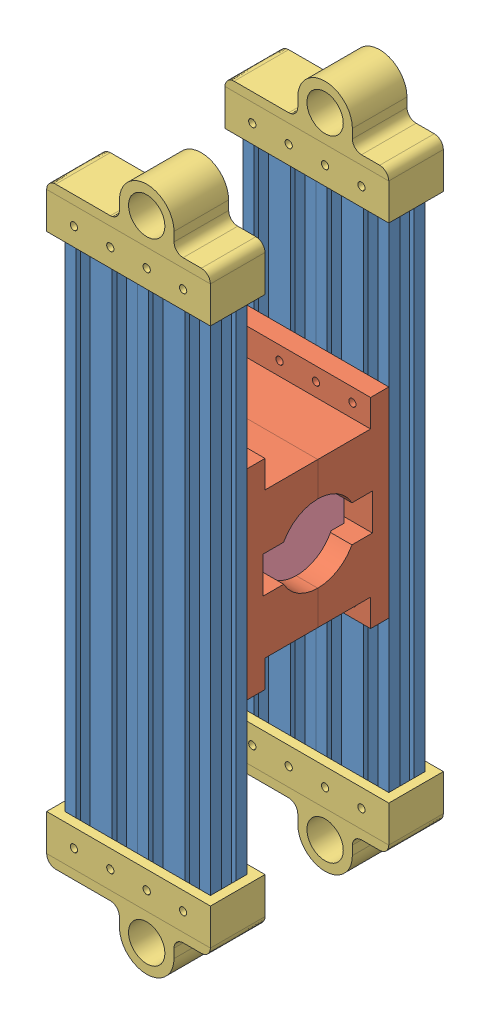
SolidWorks assembly Suspension complète v1.0, configuration Défaut. Lengths in mm.
Overall size (108 375.2 128).
13 component instances, 4 part files, 8 mates.
Components (placement in the parent):
- suspension1.0-1: suspension1.0 [Défaut] at (22.9768 47.3226 -340) size (90 375.2 64)
  - profilé 370-40-1: profilé 370-40 [Défaut] at (-82.9768 -150.3226 340) size (40 316 20)
  - profilé 370-40-2: profilé 370-40 [Défaut] at (-42.9768 -150.3226 340) size (40 316 20)
  - support moteur-2: support moteur [Défaut] at (-47.9768 7.6774 359.5) x (0 -1 0) z (-1 0 0) size (110 39 80)
  - fin profilé-1: fin profilé [Défaut] at (-62.9768 165.6774 330) x (-1 0 0) z (0 -1 0) size (90 30 49.6)
  - fin profilé-2: fin profilé [Défaut] at (-62.9768 -150.3226 330) x (-1 0 0) z (0 1 0) size (90 30 49.6)
- suspension1.0-2: suspension1.0 [Défaut] at (22.9768 62.6774 418) x (1 0 0) z (0 0 -1) size (90 375.2 64)
  - profilé 370-40-1: profilé 370-40 [Défaut] at (-82.9768 -150.3226 340) size (40 316 20)
  - profilé 370-40-2: profilé 370-40 [Défaut] at (-42.9768 -150.3226 340) size (40 316 20)
  - support moteur-2: support moteur [Défaut] at (-47.9768 7.6774 359.5) x (0 -1 0) z (-1 0 0) size (110 39 80)
  - fin profilé-1: fin profilé [Défaut] at (-62.9768 165.6774 330) x (-1 0 0) z (0 -1 0) size (90 30 49.6)
  - fin profilé-2: fin profilé [Défaut] at (-62.9768 -150.3226 330) x (-1 0 0) z (0 1 0) size (90 30 49.6)
- moteur-1: moteur [Défaut] at (-11.6 55 39) x (0 -1 0) z (-1 0 0) size (42 47 91.4)
Mates (geometry in assembly coordinates):
- Coïncidente2: coincident: point of suspension1.0-1/support moteur-2
- Coïncidente3: coincident aligned: plane of suspension1.0-1/support moteur-2 through (0 55 19.5) normal (1 0 0)
- Parallèle1: parallel anti-aligned: plane of suspension1.0-1/support moteur-2 through (-80 15 19.5) normal (0 -1 0)
- Coïncidente5: coincident anti-aligned: plane of suspension1.0-1/support moteur-2 through (-80 55 39) normal (0 0 1); plane of suspension1.0-2/support moteur-2 through (-80 55 39) normal (0 0 -1)
- Coïncidente6: coincident: point of suspension1.0-1/support moteur-2; point of suspension1.0-2/support moteur-2
- Coïncidente7: coincident: point of suspension1.0-1/support moteur-2; point of suspension1.0-2/support moteur-2
- Coaxiale1: concentric aligned: cylinder of suspension1.0-2/support moteur-2 through (-80 55 39) axis (1 0 0) radius 21.25; cylinder of moteur-1 through (-80 55 39) axis (1 0 0) radius 21
- Coïncidente8: coincident aligned: plane of suspension1.0-2/support moteur-2 through (-80 55 58.5) normal (-1 0 0); circle of moteur-1
